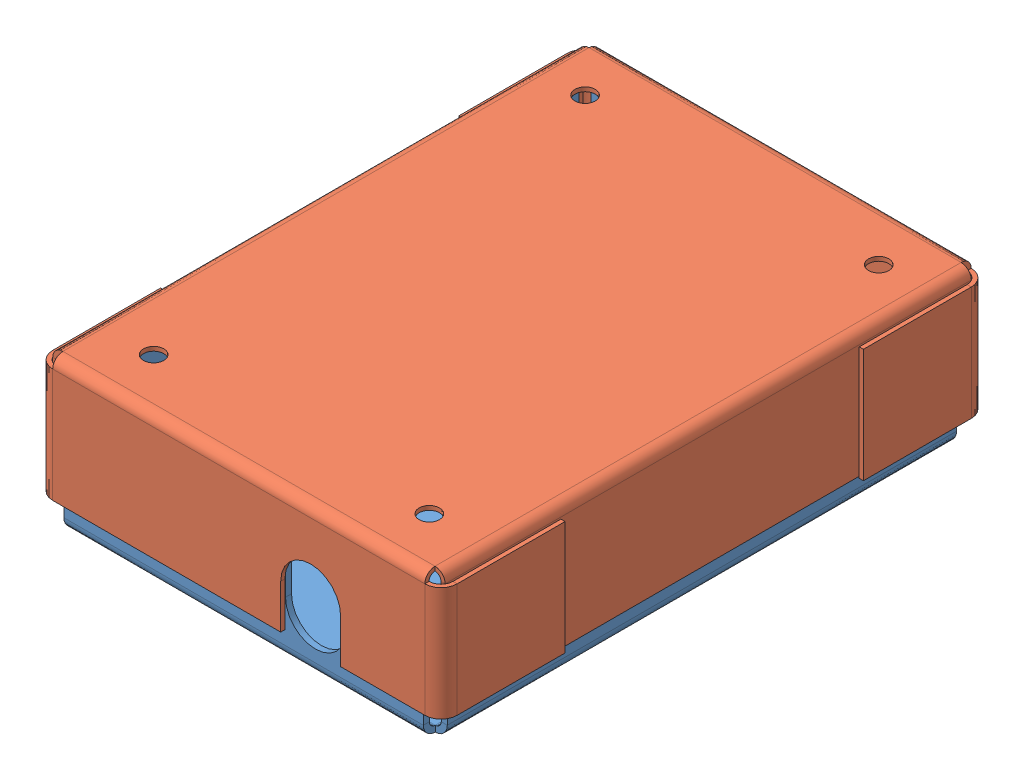
SolidWorks assembly IR Box, configuration Default. Lengths in mm.
Overall size (67.5 25.06 91.2).
2 component instances, 2 part files, 3 mates.
Components (placement in the parent):
- IR Box Bottom-1: IR Box Bottom [Default] at origin size (64 21 89)
- IR Box Top-1: IR Box Top [Default] at (-1.05 24.0608 -1.7) size (67.5 20.7 91.2)
Mates (geometry in assembly coordinates):
- Parallel1: parallel aligned: plane of IR Box Bottom-1 through (0 0 87) normal (0 0 1); plane of IR Box Top-1 through (-1.05 24.0608 87.8) normal (0 0 1)
- Parallel2: parallel aligned: plane of IR Box Bottom-1 through (62 0 0) normal (1 0 0); plane of IR Box Top-1 through (62.75 24.0608 -1.7) normal (1 0 0)
- Concentric1: concentric aligned: circle of IR Box Bottom-1; circle of IR Box Top-1
